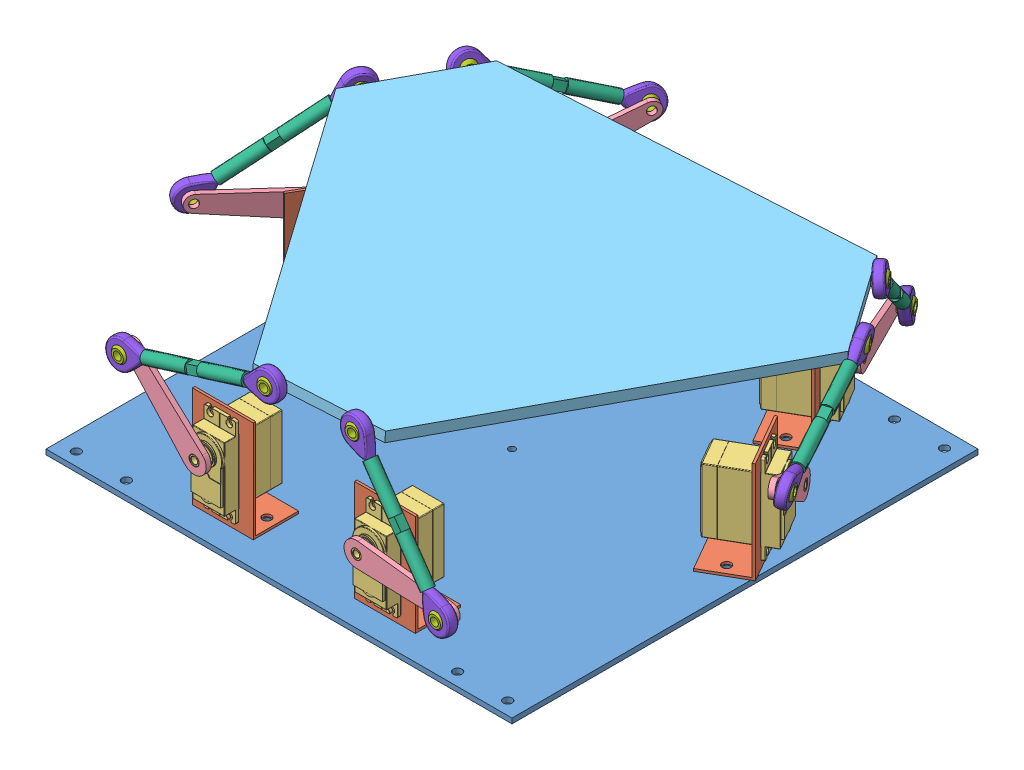
SolidWorks assembly Platform assem, configuration Default. Lengths in mm.
Overall size (410.43 122.91 388.59).
56 component instances, 8 part files, 36 mates.
Components (placement in the parent):
- bottom platform-1: bottom platform [Default] at origin size (292.1 3.17 292.1)
- servo mount-1: servo mount [Default] at (-50.8 3.175 102.0536) x (-1 0 0) z (0 0 -1) size (38.1 63.5 28.38)
- Servo Motor-1: Servo Motor [Varsayılan] at (-50.831 35.6845 102.4343) x (0 -1 0) z (0 0 1) size (56 20.04 46)
- servo mount-7: servo mount [Default] at (50.8 3.175 102.0536) x (-1 0 0) z (0 0 -1) size (38.1 63.5 28.38)
- Servo Motor-7: Servo Motor [Varsayılan] at (50.769 35.6845 102.4343) x (0 -1 0) z (0 0 1) size (56 20.04 46)
- servo arm-1: servo arm [Default] at (-50.831 45.6845 148.4343) x (-0.70276 0.711427 0) z (0 0 -1) size (69.85 15.24 3.17)
- servo arm-2: servo arm [Default] at (50.769 45.6845 148.4343) x (0.997194 -0.074867 0) z (0 0 -1) size (69.85 15.24 3.17)
- servo arm-3: servo arm [Default] at (151.1827 45.6845 -28.6624) x (0.42186 0.536782 0.730684) z (0.866025 0 -0.5) size (69.85 15.24 3.17)
- servo arm-4: servo arm [Default] at (100.4137 45.6845 -116.5969) x (-0.492504 -0.172506 -0.853042) z (0.866025 0 -0.5) size (69.85 15.24 3.17)
- servo arm-5: servo arm [Default] at (-100.3827 45.6845 -116.6506) x (0.457629 0.402869 -0.792636) z (-0.866025 0 -0.5) size (69.85 15.24 3.17)
- servo arm-6: servo arm [Default] at (-151.2137 45.6845 -28.6087) x (-0.490793 0.191019 0.850079) z (-0.866025 0 -0.5) size (69.85 15.24 3.17)
- upper platform-1: upper platform [Default] at (7.8064 101.7733 -4.763) x (0.578973 0.016195 0.815186) z (-0.814857 0.046144 0.577823) size (295.18 6.35 255.64)
- Rod assem-1: Rod assem [Default] at (176.1968 79.7217 -3.0023) x (0.219475 0.961545 0.165112) z (-0.898904 0.133519 0.417307) size (18 109.5 10.52) (flexible)
  - platform rods-1: platform rods [Default] at origin size (7.37 63.5 7.37)
  - uxcell SA5T ball-1: uxcell SA5T ball [Default] at (0 -14 0) x (0.508065 0.846902 0.156928) z (-0.107515 -0.118412 0.987127) size (11.01 11.01 8)
  - uxcell SA5T ball joint housing-1: uxcell SA5T ball joint housing [Default] at (0 -14 0) size (18 42.37 10.1)
  - uxcell SA5T ball joint housing-2: uxcell SA5T ball joint housing [Default] at (0 77.5 0) x (-1 0 0) z (0 0 1) size (18 42.37 10.1)
  - uxcell SA5T ball-2: uxcell SA5T ball [Default] at (0 77.5 0) x (0.42641 0.883481 0.193998) z (-0.039066 -0.196286 0.979768) size (11.01 11.01 8)
- Rod assem-11: Rod assem [Default] at (84.435 45.2622 -160.4799) x (0.473077 -0.734488 0.486545) z (-0.771568 -0.078805 0.631247) size (18 109.5 10.48) (flexible)
  - platform rods-1: platform rods [Default] at origin size (7.37 63.5 7.37)
  - uxcell SA5T ball-1: uxcell SA5T ball [Default] at (0 -14 0) x (-0.985157 0.053743 -0.163027) z (-0.166424 -0.066328 0.983821) size (11.01 11.01 8)
  - uxcell SA5T ball joint housing-1: uxcell SA5T ball joint housing [Default] at (0 -14 0) size (18 42.37 10.1)
  - uxcell SA5T ball joint housing-2: uxcell SA5T ball joint housing [Default] at (0 77.5 0) x (-1 0 0) z (0 0 1) size (18 42.37 10.1)
  - uxcell SA5T ball-2: uxcell SA5T ball [Default] at (0 77.5 0) x (-0.95124 -0.282746 -0.123275) z (-0.138246 0.033541 0.98983) size (11.01 11.01 8)
- Rod assem-12: Rod assem [Default] at (98.5384 51.8689 151.2048) x (0.749139 0.662186 0.017349) z (-0.071116 0.05436 0.995986) size (18 109.5 10.32) (flexible)
  - platform rods-1: platform rods [Default] at origin size (7.37 63.5 7.37)
  - uxcell SA5T ball-1: uxcell SA5T ball [Default] at (0 -14 0) x (-0.018699 0.995933 0.088136) z (0.017349 -0.087815 0.995986) size (11.01 11.01 8)
  - uxcell SA5T ball joint housing-1: uxcell SA5T ball joint housing [Default] at (0 -14 0) size (18 42.37 10.1)
  - uxcell SA5T ball joint housing-2: uxcell SA5T ball joint housing [Default] at (0 77.5 0) x (-1 0 0) z (0 0 1) size (18 42.37 10.1)
  - uxcell SA5T ball-2: uxcell SA5T ball [Default] at (0 77.5 0) x (-0.280735 0.948182 0.148791) z (0.112227 -0.121532 0.986223) size (11.01 11.01 8)
- Rod assem-13: Rod assem [Default] at (-86.505 74.277 -154.2128) x (-0.072634 0.879062 -0.471141) z (0.898462 0.262758 0.351746) size (18 109.5 11.48) (flexible)
  - platform rods-1: platform rods [Default] at origin size (7.37 63.5 7.37)
  - uxcell SA5T ball-1: uxcell SA5T ball [Default] at (0 -14 0) x (0.27057 0.961129 0.054981) z (-0.298473 0.029453 0.953963) size (11.01 11.01 8)
  - uxcell SA5T ball joint housing-1: uxcell SA5T ball joint housing [Default] at (0 -14 0) size (18 42.37 10.1)
  - uxcell SA5T ball joint housing-2: uxcell SA5T ball joint housing [Default] at (0 77.5 0) x (-1 0 0) z (0 0 1) size (18 42.37 10.1)
  - uxcell SA5T ball-2: uxcell SA5T ball [Default] at (0 77.5 0) x (0.057628 0.995276 0.078131) z (-0.270459 -0.059771 0.960874) size (11.01 11.01 8)
- Rod assem-14: Rod assem [Default] at (-178.7026 64.3958 6.9326) x (0.210178 -0.822886 -0.527904) z (0.849548 -0.113499 0.515157) size (18 109.5 10.19) (flexible)
  - platform rods-1: platform rods [Default] at origin size (7.37 63.5 7.37)
  - uxcell SA5T ball-1: uxcell SA5T ball [Default] at (0 -14 0) x (-0.971257 -0.230013 -0.061265) z (-0.081932 0.081398 0.993308) size (11.01 11.01 8)
  - uxcell SA5T ball joint housing-1: uxcell SA5T ball joint housing [Default] at (0 -14 0) size (18 42.37 10.1)
  - uxcell SA5T ball joint housing-2: uxcell SA5T ball joint housing [Default] at (0 77.5 0) x (-1 0 0) z (0 0 1) size (18 42.37 10.1)
  - uxcell SA5T ball-2: uxcell SA5T ball [Default] at (0 77.5 0) x (-0.82505 -0.560858 0.068772) z (-0.021706 0.153076 0.987976) size (11.01 11.01 8)
- Rod assem-15: Rod assem [Default] at (-77.5389 90.1777 151.9263) x (0.275971 -0.958238 0.074967) z (0.014232 0.082061 0.996526) size (18 109.5 10.1) (flexible)
  - platform rods-1: platform rods [Default] at origin size (7.37 63.5 7.37)
  - uxcell SA5T ball-1: uxcell SA5T ball [Default] at (0 -14 0) x (-0.874696 -0.482266 0.048243) z (0.074967 -0.036284 0.996526) size (11.01 11.01 8)
  - uxcell SA5T ball joint housing-1: uxcell SA5T ball joint housing [Default] at (0 -14 0) size (18 42.37 10.1)
  - uxcell SA5T ball joint housing-2: uxcell SA5T ball joint housing [Default] at (0 77.5 0) x (-1 0 0) z (0 0 1) size (18 42.37 10.1)
  - uxcell SA5T ball-2: uxcell SA5T ball [Default] at (0 77.5 0) x (0.949702 -0.31034 -0.041898) z (0.064971 0.064382 0.995808) size (11.01 11.01 8)
- servo mount-12: servo mount [Default] at (113.781 3.175 -7.0327) x (0.5 0 0.866025) z (-0.866025 0 0.5) size (38.1 63.5 28.38)
- servo mount-13: servo mount [Default] at (62.981 3.175 -95.0209) x (0.5 0 0.866025) z (-0.866025 0 0.5) size (38.1 63.5 28.38)
- servo mount-14: servo mount [Default] at (-113.781 3.175 -7.0327) x (0.5 0 -0.866025) z (0.866025 0 0.5) size (38.1 63.5 28.38)
- servo mount-15: servo mount [Default] at (-62.981 3.175 -95.0209) x (0.5 0 -0.866025) z (0.866025 0 0.5) size (38.1 63.5 28.38)
- Servo Motor-12: Servo Motor [Varsayılan] at (-114.1262 35.6845 -7.1962) x (0 -1 0) z (-0.866025 0 -0.5) size (56 20.04 46)
- Servo Motor-13: Servo Motor [Varsayılan] at (-63.2952 35.6845 -95.2381) x (0 -1 0) z (-0.866025 0 -0.5) size (56 20.04 46)
- Servo Motor-14: Servo Motor [Varsayılan] at (114.0952 35.6845 -7.2499) x (0 -1 0) z (0.866025 0 -0.5) size (56 20.04 46)
- Servo Motor-15: Servo Motor [Varsayılan] at (63.3262 35.6845 -95.1844) x (0 -1 0) z (0.866025 0 -0.5) size (56 20.04 46)
Mates (geometry in assembly coordinates):
- Concentric8: concentric anti-aligned: cylinder of Servo Motor-1 through (-50.831 45.6845 148.4343) axis (0 0 -1) radius 3; cylinder of servo arm-1 through (-50.831 45.6845 145.2593) axis (0 0 1) radius 3.175
- Coincident13: coincident aligned: plane of Servo Motor-1 through (-50.831 45.6845 148.4343) normal (0 0 1); plane of servo arm-1 through (-50.831 45.6845 148.4343) normal (0 0 1)
- Concentric13: concentric anti-aligned: cylinder of Servo Motor-7 through (50.769 45.6845 148.4343) axis (0 0 -1) radius 3; cylinder of servo arm-2 through (50.769 45.6845 145.2593) axis (0 0 1) radius 3.175
- Coincident12: coincident aligned: plane of Servo Motor-7 through (50.769 45.6845 148.4343) normal (0 0 1); plane of servo arm-2 through (50.769 45.6845 148.4343) normal (0 0 1)
- Coincident620: coincident anti-aligned: plane of servo arm-3 through (153.9323 45.6845 -30.2499) normal (0.866025 0 -0.5); plane of Rod assem-1/uxcell SA5T ball-1 through (178.0417 76.3616 11.5087) normal (-0.866025 0 0.5)
- Coincident622: coincident anti-aligned: plane of upper platform-1 through (150.991 101.8837 -59.722) normal (0.814857 -0.046144 -0.577823); plane of Rod assem-1/uxcell SA5T ball-2 through (143.5483 98.5069 -69.9481) normal (-0.814857 0.046144 0.577823)
- Coincident628: coincident anti-aligned: plane of upper platform-1 through (150.991 101.8837 -59.722) normal (0.814857 -0.046144 -0.577823); plane of Rod assem-11/uxcell SA5T ball-2 through (114.1364 97.6842 -111.3596) normal (-0.814857 0.046144 0.577823)
- Coincident630: coincident anti-aligned: plane of servo arm-4 through (103.1633 45.6845 -118.1844) normal (0.866025 0 -0.5); plane of Rod assem-11/uxcell SA5T ball-1 through (75.0167 35.8258 -166.9357) normal (-0.866025 0 0.5)
- Coincident633: coincident anti-aligned: plane of servo arm-5 through (-103.1323 45.6845 -118.2381) normal (-0.866025 0 -0.5); plane of Rod assem-13/uxcell SA5T ball-1 through (-76.9788 68.7084 -163.5372) normal (0.866025 0 0.5)
- Coincident635: coincident anti-aligned: plane of upper platform-1 through (-111.0519 107.6275 -101.514) normal (-0.908834 0.009047 -0.41706); plane of Rod assem-13/uxcell SA5T ball-2 through (-116.4273 105.0667 -89.8557) normal (0.908834 -0.009047 0.41706)
- Coincident637: coincident anti-aligned: plane of upper platform-1 through (-111.0519 107.6275 -101.514) normal (-0.908834 0.009047 -0.41706); plane of Rod assem-14/uxcell SA5T ball-2 through (-137.5703 107.5081 -43.7292) normal (0.908834 -0.009047 0.41706)
- Coincident641: coincident anti-aligned: plane of servo arm-6 through (-153.9633 45.6845 -30.1962) normal (-0.866025 0 -0.5); plane of Rod assem-14/uxcell SA5T ball-1 through (-182.0122 56.6012 18.3858) normal (0.866025 0 0.5)
- Coincident643: coincident anti-aligned: plane of servo arm-1 through (-50.831 45.6845 148.4343) normal (0 0 1); plane of Rod assem-15/uxcell SA5T ball-1 through (-90.9937 86.3425 148.4343) normal (0 0 -1)
- Coincident645: coincident anti-aligned: plane of upper platform-1 through (-15.9816 114.836 146.1868) normal (0.093977 0.037097 0.994883); plane of Rod assem-15/uxcell SA5T ball-2 through (-3.4326 111.2601 145.1347) normal (-0.093977 -0.037097 -0.994883)
- Coincident647: coincident anti-aligned: plane of servo arm-2 through (50.769 45.6845 148.4343) normal (0 0 1); plane of Rod assem-12/uxcell SA5T ball-1 through (107.7586 41.4058 148.4343) normal (0 0 -1)
- Coincident649: coincident anti-aligned: plane of upper platform-1 through (-15.9816 114.836 146.1868) normal (0.093977 0.037097 0.994883); plane of Rod assem-12/uxcell SA5T ball-2 through (47.1222 109.6414 140.4197) normal (-0.093977 -0.037097 -0.994883)
- Concentric25: concentric aligned: cylinder of servo arm-6 through (-153.9633 45.6845 -30.1962) axis (0.866025 0 0.5) radius 3.175; cylinder of Servo Motor-12 through (-153.9633 45.6845 -30.1962) axis (0.866025 0 0.5) radius 2
- Coincident655: coincident aligned: plane of servo arm-6 through (-153.9633 45.6845 -30.1962) normal (-0.866025 0 -0.5); plane of Servo Motor-12 through (-153.9633 45.6845 -30.1962) normal (-0.866025 0 -0.5)
- Concentric28: concentric aligned: cylinder of servo arm-5 through (-103.1323 45.6845 -118.2381) axis (0.866025 0 0.5) radius 3.175; cylinder of Servo Motor-13 through (-103.1323 45.6845 -118.2381) axis (0.866025 0 0.5) radius 2
- Coincident657: coincident aligned: plane of servo arm-5 through (-103.1323 45.6845 -118.2381) normal (-0.866025 0 -0.5); plane of Servo Motor-13 through (-103.1323 45.6845 -118.2381) normal (-0.866025 0 -0.5)
- Concentric29: concentric anti-aligned: cylinder of upper platform-1 through (-116.4273 105.0667 -89.8557) axis (-0.908834 0.009047 -0.41706) radius 2.1; cylinder of Rod assem-13/uxcell SA5T ball-2 through (-125.0658 105.1527 -93.8198) axis (0.908834 -0.009047 0.41706) radius 2.5
- Concentric30: concentric anti-aligned: cylinder of upper platform-1 through (-137.5703 107.5081 -43.7292) axis (-0.908834 0.009047 -0.41706) radius 2.1; cylinder of Rod assem-14/uxcell SA5T ball-2 through (-146.2088 107.5941 -47.6933) axis (0.908834 -0.009047 0.41706) radius 2.5
- Concentric31: concentric aligned: cylinder of servo arm-6 through (-182.0122 56.6012 18.3858) axis (0.866025 0 0.5) radius 2.54; cylinder of Rod assem-14/uxcell SA5T ball-1 through (-190.2437 56.6012 13.6333) axis (0.866025 0 0.5) radius 2.5
- Concentric33: concentric aligned: cylinder of servo arm-5 through (-76.9788 68.7084 -163.5372) axis (0.866025 0 0.5) radius 2.54; cylinder of Rod assem-13/uxcell SA5T ball-1 through (-85.2104 68.7084 -168.2897) axis (0.866025 0 0.5) radius 2.5
- Concentric36: concentric aligned: cylinder of servo arm-4 through (103.1633 45.6845 -118.1844) axis (-0.866025 0 0.5) radius 3.175; cylinder of Servo Motor-15 through (103.1633 45.6845 -118.1844) axis (-0.866025 0 0.5) radius 2
- Coincident659: coincident aligned: plane of servo arm-4 through (103.1633 45.6845 -118.1844) normal (0.866025 0 -0.5); plane of Servo Motor-15 through (103.1633 45.6845 -118.1844) normal (0.866025 0 -0.5)
- Concentric37: concentric aligned: cylinder of servo arm-4 through (75.0167 35.8258 -166.9357) axis (-0.866025 0 0.5) radius 2.54; cylinder of Rod assem-11/uxcell SA5T ball-1 through (83.2483 35.8258 -171.6882) axis (-0.866025 0 0.5) radius 2.5
- Concentric38: concentric anti-aligned: cylinder of upper platform-1 through (114.1364 97.6842 -111.3596) axis (0.814857 -0.046144 -0.577823) radius 2.1; cylinder of Rod assem-11/uxcell SA5T ball-2 through (121.8817 97.2456 -116.8518) axis (-0.814857 0.046144 0.577823) radius 2.5
- Concentric41: concentric anti-aligned: cylinder of upper platform-1 through (143.5483 98.5069 -69.9481) axis (0.814857 -0.046144 -0.577823) radius 2.1; cylinder of Rod assem-1/uxcell SA5T ball-2 through (151.2935 98.0683 -75.4403) axis (-0.814857 0.046144 0.577823) radius 2.5
- Concentric42: concentric aligned: cylinder of servo arm-3 through (178.0417 76.3616 11.5087) axis (-0.866025 0 0.5) radius 2.54; cylinder of Rod assem-1/uxcell SA5T ball-1 through (186.2732 76.3616 6.7562) axis (-0.866025 0 0.5) radius 2.5
- Concentric43: concentric aligned: cylinder of servo arm-3 through (153.9323 45.6845 -30.2499) axis (-0.866025 0 0.5) radius 3.175; cylinder of Servo Motor-14 through (153.9323 45.6845 -30.2499) axis (-0.866025 0 0.5) radius 2
- Coincident661: coincident aligned: plane of servo arm-3 through (153.9323 45.6845 -30.2499) normal (0.866025 0 -0.5); plane of Servo Motor-14 through (153.9323 45.6845 -30.2499) normal (0.866025 0 -0.5)
- Concentric44: concentric aligned: cylinder of servo arm-1 through (-90.9937 86.3425 145.2593) axis (0 0 1) radius 2.54; cylinder of Rod assem-15/uxcell SA5T ball-1 through (-90.9937 86.3425 146.9293) axis (0 0 1) radius 2.5
- Concentric45: concentric aligned: cylinder of upper platform-1 through (-3.4326 111.2601 145.1347) axis (0.093977 0.037097 0.994883) radius 2.1; cylinder of Rod assem-15/uxcell SA5T ball-2 through (-3.574 111.2043 143.6374) axis (0.093977 0.037097 0.994883) radius 2.5
- Concentric46: concentric aligned: cylinder of servo arm-2 through (107.7586 41.4058 145.2593) axis (0 0 1) radius 2.54; cylinder of Rod assem-12/uxcell SA5T ball-1 through (107.7586 41.4058 146.9293) axis (0 0 1) radius 2.5
- Concentric47: concentric aligned: cylinder of upper platform-1 through (47.1222 109.6414 140.4197) axis (0.093977 0.037097 0.994883) radius 2.1; cylinder of Rod assem-12/uxcell SA5T ball-2 through (46.9808 109.5855 138.9224) axis (0.093977 0.037097 0.994883) radius 2.5
